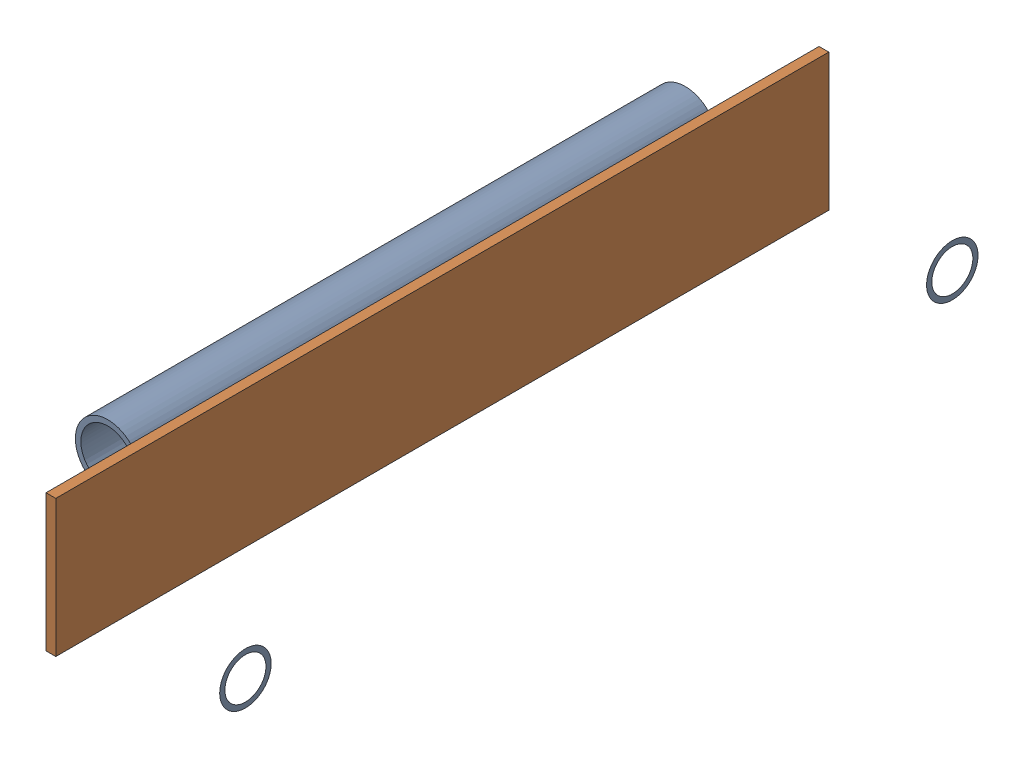
SolidWorks assembly FE-00018_, configuration Default. Lengths in mm.
Overall size (152.39 88.9 501.65).
5 component instances, 4 part files, 0 mates.
Components (placement in the parent):
- FE-00018-01_-1: FE-00018-01_ [Default] at origin size (42.06 42.06 374.65)
- FE-00018-02_-1: FE-00018-02_ [Default] at (131.3624 -37.6746 -42.037) x (0 0 1) z (-1 0 0) size (33.4 33.4 101.6)
- FE-00018-02_-2: FE-00018-02_ [Default] at (131.3624 -37.6746 416.687) x (0 0 1) z (-1 0 0) size (33.4 33.4 101.6)
- FE-00018-03_-1: FE-00018-03_ [Default] at (29.7624 24.9999 412.75) x (0 0 -1) z (-1 0 0) size (501.65 88.9 6.35)
- FE-00018-04_-1: FE-00018-04_ [Default] at (17.8562 -7.9439 0) x (0 -1 0) z (0 0 1) size (12.7 2.38 374.65)
